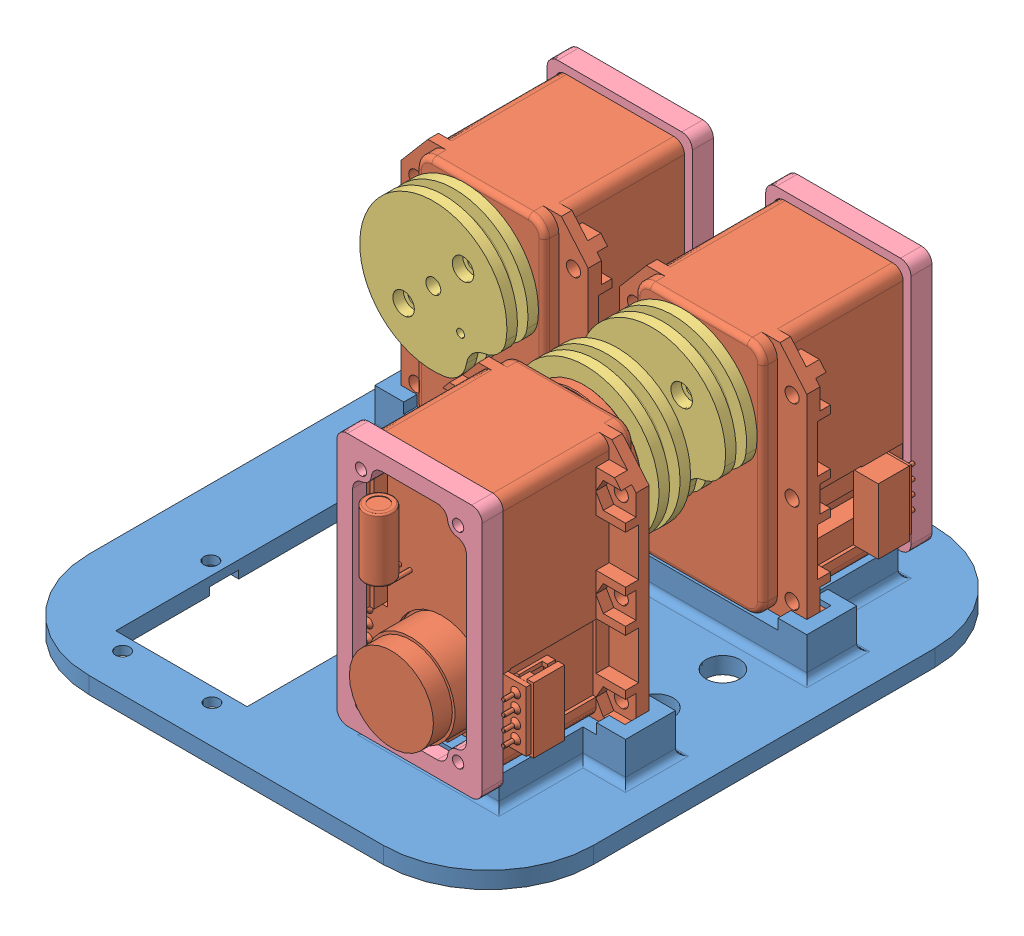
SolidWorks assembly wrist_block, configuration Default. Lengths in mm.
Overall size (96 61.57 105).
17 component instances, 5 part files, 13 mates.
Components (placement in the parent):
- w_t1-1: w_t1 [Default] at (-39.4578 -5.4849 22.8492) size (96 10.68 105)
- pulley_MX-28-1: pulley_MX-28 [Default] at (-18.6578 36.2901 -7.1508) size (38.36 58.4 42.92)
  - dynamixel MX-28-exposed-1: dynamixel MX-28-exposed [Back Off] at origin size (35.6 50.6 39.77)
  - w_p1-1: w_p1 [Default] at (0 0 23.67) x (0.707107 -0.707107 0) z (0 0 1) size (26.25 28 6)
  - w_ac-1: w_ac [Default] at (12.375 12.125 -8.75) x (0 -1 0) z (0 0 -1) size (48.25 27.65 4)
- pulley_MX-28-2: pulley_MX-28 [Default] at (-18.6578 36.2901 52.8492) x (-1 0 0) z (0 0 -1) size (38.36 58.4 42.92)
  - dynamixel MX-28-exposed-1: dynamixel MX-28-exposed [Back Off] at origin size (35.6 50.6 39.77)
  - w_p1-1: w_p1 [Default] at (0 0 23.67) x (0.707107 -0.707107 0) z (0 0 1) size (26.25 28 6)
  - w_ac-1: w_ac [Default] at (12.375 12.125 -8.75) x (0 -1 0) z (0 0 -1) size (48.25 27.65 4)
- pulley_MX-28-3: pulley_MX-28 [Default] at (-60.2578 36.2901 -7.1508) size (38.36 58.4 42.92)
  - dynamixel MX-28-exposed-1: dynamixel MX-28-exposed [Back Off] at origin size (35.6 50.6 39.77)
  - w_p1-1: w_p1 [Default] at (0 0 23.67) x (0.707107 -0.707107 0) z (0 0 1) size (26.25 28 6)
  - w_ac-1: w_ac [Default] at (12.375 12.125 -8.75) x (0 -1 0) z (0 0 -1) size (48.25 27.65 4)
- gear_MX-28-1: gear_MX-28 [Default] at (-51.1573 48.1448 74.2289) x (-1 0 0) z (0 -1 0) size (35.6 52.23 39.77) (hidden)
  - dynamixel MX-28-exposed-1: dynamixel MX-28-exposed [Back Off] at (8.6005 39.3797 35.4547) size (35.6 50.6 39.77)
  - w_g1-2: w_g1 [Default] at (8.6005 39.3797 55.9747) size (25.49 25.49 3)
  - w_ac-1: w_ac [Default] at (20.9755 51.5047 26.7047) x (0 -1 0) z (0 0 -1) size (48.25 27.65 4)
Mates (geometry in assembly coordinates):
- Coincident1: coincident anti-aligned: plane of w_t1-1 through (-39.4578 3.1901 7.8492) normal (0 0 -1); plane of pulley_MX-28-1/dynamixel MX-28-exposed-1 through (-18.6578 36.2901 7.8492) normal (0 0 1)
- Coincident2: coincident anti-aligned: plane of w_t1-1 through (-0.8578 3.1901 22.8492) normal (-1 0 0); plane of pulley_MX-28-1/dynamixel MX-28-exposed-1 through (-0.8578 3.6901 5.8492) normal (1 0 0)
- Coincident3: coincident anti-aligned: plane of w_t1-1 through (-39.4578 -2.3099 22.8492) normal (0 1 0); plane of pulley_MX-28-1/dynamixel MX-28-exposed-1 through (-31.3578 -2.3099 5.8492) normal (0 -1 0)
- Coincident13: coincident anti-aligned: plane of w_t1-1 through (-39.4578 -2.3099 22.8492) normal (0 1 0); plane of pulley_MX-28-3/dynamixel MX-28-exposed-1 through (-72.9578 -2.3099 5.8492) normal (0 -1 0)
- Coincident15: coincident anti-aligned: plane of w_t1-1 through (-39.4578 3.1901 7.8492) normal (0 0 -1); plane of pulley_MX-28-3/dynamixel MX-28-exposed-1 through (-60.2578 36.2901 7.8492) normal (0 0 1)
- Coincident16: coincident anti-aligned: plane of w_t1-1 through (-42.4578 3.1901 22.8492) normal (-1 0 0); plane of pulley_MX-28-3/dynamixel MX-28-exposed-1 through (-42.4578 3.6901 5.8492) normal (1 0 0)
- Coincident17: coincident anti-aligned: plane of w_t1-1 through (-39.4578 -2.3099 22.8492) normal (0 1 0); plane of pulley_MX-28-2/dynamixel MX-28-exposed-1 through (-5.9578 -2.3099 39.8492) normal (0 -1 0)
- Concentric1: concentric anti-aligned: circle of w_t1-1; circle of gear_MX-28-1/dynamixel MX-28-exposed-1
- Concentric2: concentric anti-aligned: circle of w_t1-1; circle of gear_MX-28-1/dynamixel MX-28-exposed-1
- Coincident23: coincident anti-aligned: plane of w_t1-1 through (-39.4578 -2.3099 22.8492) normal (0 1 0); plane of gear_MX-28-1/dynamixel MX-28-exposed-1 through (-59.7578 -2.3099 34.8492) normal (0 -1 0)
- Coincident24: coincident: plane of w_t1-1 through (-39.4578 -2.3099 22.8492) normal (0 1 0); plane of gear_MX-28-1/dynamixel MX-28-exposed-1 through (-59.7578 -2.3099 34.8492) normal (0 -1 0)
- Concentric3: concentric: circle of w_t1-1; circle of gear_MX-28-1/dynamixel MX-28-exposed-1
- Concentric4: concentric anti-aligned: circle of w_t1-1; circle of gear_MX-28-1/dynamixel MX-28-exposed-1
